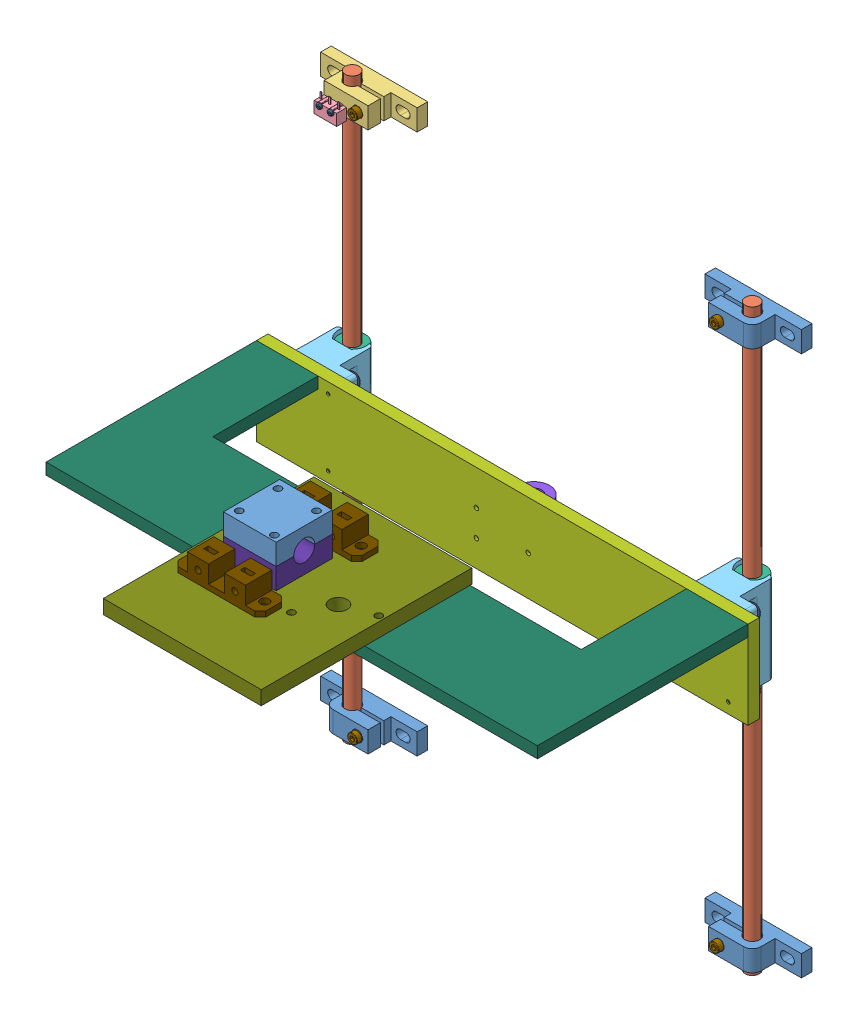
SolidWorks assembly moving assembly, configuration Default. Lengths in mm.
Overall size (280 330 218.5).
61 component instances, 19 part files, 106 mates.
Components (placement in the parent):
- bar_and_mounts-1: bar_and_mounts [Default] at (-49.2169 -149.0461 22.6055) size (55 330 19)
  - bar_mount-1: bar_mount [Default] at (-61.595 -12.5462 12.9389) size (55 12 19)
  - bar_mount-2: bar_mount [Default] at (-61.595 295.4538 12.9389) size (55 12 19)
  - bar-1: bar [Default] at (-29.595 -17.5462 23.9389) size (8 330 8)
- bar_and_mounts_switch-1: bar_and_mounts_switch [Default] at (-356.8295 169.2155 27.6951) x (-1 0 0) z (0 0 1) size (55 330 24.7)
  - bar_mount_switch-1: bar_mount_switch [Default] at (-82.0176 10.8078 7.8492) size (55 12 19)
  - bar-1: bar [Default] at (-50.0176 5.8078 18.8492) size (8 330 8)
  - bar_mount-1: bar_mount [Default] at (-82.0176 318.8078 7.8492) size (55 12 19)
  - switch-1: switch [Default] at (-54.8176 17.8078 26.8492) x (1 0 0) z (0 -1 0) size (12.8 5.7 10.85)
- pusher_bearing_mount-1: pusher_bearing_mount [Default] at (-93.535 -18.6939 68.5444) size (40 50 27.5)
- pusher_bearing_mount-2: pusher_bearing_mount [Default] at (-321.535 -18.6939 68.5444) size (40 50 27.5)
- lm8uul-1: lm8uul [Default] at (-78.8119 -15.6939 46.5444) size (15 45 15)
- lm8uul-2: lm8uul [Default] at (-306.8119 -15.6939 46.5444) size (15 45 15)
- pusher_plank-1: pusher_plank [Default] at (-332.8119 -18.6939 68.5444) x (1 0 0) z (0 -1 0) size (280 6.5 50)
- pusher_mount-1: pusher_mount [Default] at (-192.8119 -8.6939 68.5444) size (40 25 20.5)
- socket head cap screw_din-2: socket head cap screw_din [DIN 912 M3 x 16 --- 16N] at (-89.8119 152.4077 57.5444) x (0 0 -1) z (1 0 0) size (19 5.5 5.5)
- socket head cap screw_din-3: socket head cap screw_din [DIN 912 M3 x 16 --- 16N] at (-295.8119 152.4077 57.5444) x (0 0 -1) z (1 0 0) size (19 5.5 5.5)
- socket head cap screw_din-4: socket head cap screw_din [DIN 912 M3 x 16 --- 16N] at (-295.8119 -155.5923 57.5444) x (0 0 -1) z (1 0 0) size (19 5.5 5.5)
- socket head cap screw_din-5: socket head cap screw_din [DIN 912 M3 x 16 --- 16N] at (-89.8119 -155.5923 57.5444) x (0 0 -1) z (1 0 0) size (19 5.5 5.5)
- slotted pan head screw_din-1: slotted pan head screw_din [ISO 1580 - M1.6 x 8 --- 8N] at (-311.6619 150.4077 61.2444) x (0 0 -1) z (1 0 0) size (9.03 3.2 3.2)
- slotted pan head screw_din-4: slotted pan head screw_din [ISO 1580 - M1.6 x 8 --- 8N] at (-305.1619 150.4077 61.2444) x (0 0 -1) z (1 0 0) size (9.03 3.2 3.2)
- slotted pan head screw_din-8: slotted pan head screw_din [ISO 1580 - M4 x 10 --- 10N] at (-207.5619 11.3061 61.1444) x (0 0 1) z (-1 0 0) size (12.47 8 8)
- slotted pan head screw_din-9: slotted pan head screw_din [ISO 1580 - M4 x 10 --- 10N] at (-178.0619 3.8061 61.1444) x (0 0 1) z (-1 0 0) size (12.47 8 8)
- slotted pan head screw_din-10: slotted pan head screw_din [ISO 1580 - M4 x 10 --- 10N] at (-207.5619 -3.6939 61.1444) x (0 0 1) z (-1 0 0) size (12.47 8 8)
- prevailing torque nut style 1 insert_din-1: prevailing torque nut style 1 insert_din [DIN EN ISO 7040 - M3 - N] at (-89.8119 152.4077 41.3944) x (0.923728 0.383049 0) z (0 0 -1) size (5.5 6.35 4.5)
- prevailing torque nut style 1 insert_din-2: prevailing torque nut style 1 insert_din [DIN EN ISO 7040 - M3 - N] at (-89.8119 -155.5923 41.3944) x (0.923728 0.383049 0) z (0 0 -1) size (5.5 6.35 4.5)
- prevailing torque nut style 1 insert_din-3: prevailing torque nut style 1 insert_din [DIN EN ISO 7040 - M3 - N] at (-295.8119 -155.5923 41.3944) x (0.923728 0.383049 0) z (0 0 -1) size (5.5 6.35 4.5)
- prevailing torque nut style 1 insert_din-4: prevailing torque nut style 1 insert_din [DIN EN ISO 7040 - M3 - N] at (-295.8119 152.4077 41.3944) x (-0.923728 -0.383049 0) z (0 0 -1) size (5.5 6.35 4.5)
- toothed lock washer 1_din-1: toothed lock washer 1_din [DIN 6797-A3.2] at (-295.8119 152.4077 54.1444) x (0 0 -1) z (1 0 0) size (0.4 5.93 6)
- toothed lock washer 1_din-2: toothed lock washer 1_din [DIN 6797-A3.2] at (-89.8119 152.4077 54.1444) x (0 0 -1) z (1 0 0) size (0.4 5.93 6)
- toothed lock washer 1_din-3: toothed lock washer 1_din [DIN 6797-A3.2] at (-89.8119 -155.5923 54.1444) x (0 0 -1) z (1 0 0) size (0.4 5.93 6)
- toothed lock washer 1_din-4: toothed lock washer 1_din [DIN 6797-A3.2] at (-295.8119 -155.5923 54.9444) x (0 0 1) z (-1 0 0) size (0.4 5.93 6)
- plain washer 6902 type abc_din-2: plain washer 6902 type abc_din [DIN 6902-A3.6] at (-207.5619 -3.6939 63.5444) x (0 0 1) z (-1 0 0) size (0.8 9 9)
- plain washer 6902 type abc_din-3: plain washer 6902 type abc_din [DIN 6902-A3.6] at (-207.5619 11.3061 63.5444) x (0 0 1) z (-1 0 0) size (0.8 9 9)
- plain washer 6902 type abc_din-4: plain washer 6902 type abc_din [DIN 6902-A3.6] at (-178.0619 3.8061 63.5444) x (0 0 1) z (-1 0 0) size (0.8 9 9)
- hex nut gradec_din-1: hex nut gradec_din [Hexagon Nut ISO 4034 - M8 - N] at (-192.8119 7.7061 57.0444) x (1 0 0) z (0 1 0) size (13 15.01 7.9)
- plain washer 6902 type abc_din-5: plain washer 6902 type abc_din [DIN 6902-A3.6] at (-321.5619 6.3061 62.7444) x (0 0 1) z (-1 0 0) size (0.8 9 9)
- plain washer 6902 type abc_din-6: plain washer 6902 type abc_din [DIN 6902-A3.6] at (-292.0619 -12.6939 63.5444) x (0 0 -1) z (1 0 0) size (0.8 9 9)
- plain washer 6902 type abc_din-7: plain washer 6902 type abc_din [DIN 6902-A3.6] at (-292.0619 25.3061 63.5444) x (0 0 -1) z (1 0 0) size (0.8 9 9)
- plain washer 6902 type abc_din-8: plain washer 6902 type abc_din [DIN 6902-A3.6] at (-64.0134 -12.6939 63.5444) x (0 0 -1) z (1 0 0) size (0.8 9 9)
- plain washer 6902 type abc_din-9: plain washer 6902 type abc_din [DIN 6902-A3.6] at (-93.5619 6.3061 63.5444) x (0 0 -1) z (1 0 0) size (0.8 9 9)
- plain washer 6902 type abc_din-10: plain washer 6902 type abc_din [DIN 6902-A3.6] at (-64.0134 25.3061 63.5444) x (0 0 -1) z (1 0 0) size (0.8 9 9)
- toothed lock washer 1_din-5: toothed lock washer 1_din [DIN 6797-A4.3] at (-93.5619 6.3061 62.2444) x (0 0 -1) z (1 0 0) size (0.5 7.91 7.91)
- toothed lock washer 1_din-6: toothed lock washer 1_din [DIN 6797-A4.3] at (-64.0134 -12.6939 62.2444) x (0 0 -1) z (1 0 0) size (0.5 7.91 7.91)
- toothed lock washer 1_din-7: toothed lock washer 1_din [DIN 6797-A4.3] at (-64.0134 25.3061 62.2444) x (0 0 -1) z (1 0 0) size (0.5 7.91 7.91)
- toothed lock washer 1_din-8: toothed lock washer 1_din [DIN 6797-A4.3] at (-292.0619 -12.6939 62.2444) x (0 0 -1) z (1 0 0) size (0.5 7.91 7.91)
- toothed lock washer 1_din-9: toothed lock washer 1_din [DIN 6797-A4.3] at (-292.0619 25.3061 62.2444) x (0 0 -1) z (1 0 0) size (0.5 7.91 7.91)
- toothed lock washer 1_din-11: toothed lock washer 1_din [DIN 6797-A4.3] at (-321.5619 6.3061 62.2444) x (0 0 -1) z (1 0 0) size (0.5 7.91 7.91)
- slotted pan head screw_din-11: slotted pan head screw_din [ISO 1580 - M4 x 12 --- 12N] at (-93.5619 6.3061 59.8444) x (0 0 1) z (-1 0 0) size (14.47 8 8)
- slotted pan head screw_din-12: slotted pan head screw_din [ISO 1580 - M4 x 12 --- 12N] at (-64.0134 25.3061 59.8444) x (0 0 1) z (-1 0 0) size (14.47 8 8)
- slotted pan head screw_din-13: slotted pan head screw_din [ISO 1580 - M4 x 12 --- 12N] at (-64.0134 -12.6939 59.8444) x (0 0 1) z (-1 0 0) size (14.47 8 8)
- slotted pan head screw_din-14: slotted pan head screw_din [ISO 1580 - M4 x 12 --- 12N] at (-321.5619 6.3061 59.8444) x (0 0 1) z (-1 0 0) size (14.47 8 8)
- slotted pan head screw_din-15: slotted pan head screw_din [ISO 1580 - M4 x 12 --- 12N] at (-292.0619 25.3061 59.8444) x (0 0 1) z (-1 0 0) size (14.47 8 8)
- slotted pan head screw_din-16: slotted pan head screw_din [ISO 1580 - M4 x 12 --- 12N] at (-292.0619 -12.6939 59.8444) x (0 0 1) z (-1 0 0) size (14.47 8 8)
- carret-1: carret [Default] at (-332.8119 31.3061 75.0444) x (1 0 0) z (0 0 -1) size (280 6.5 120)
- head_assembly-1: head_assembly [Default] at (-193.7359 2.3231 248.2305) x (1 0 0) z (0 1 0) size (90 120 32)
  - laserhead_base-1: laserhead_base [Default] at (-47.4396 -5.8139 28.9831) size (90 120 8)
  - mount-1: mount [Default] at (-1.9396 79.1861 36.9831) x (0 -1 0) z (-1 0 0) size (32 12 30)
  - calibration-1: calibration [Default] at (-41.9396 28.1861 36.9831) size (50 15 13)
  - calibration-2: calibration [Default] at (-41.9396 83.1861 36.9831) size (50 15 13)
  - mount_top-1: mount_top [Default] at (-31.9396 79.1861 60.9831) x (1 0 0) z (0 1 0) size (30 12 32)
Mates (geometry in assembly coordinates):
- Coincident2: coincident aligned: plane of bar_and_mounts-1/bar_mount-1 through (-110.8119 -161.5923 41.5444) normal (0 -1 0); plane of bar_and_mounts_switch-1/bar_mount-1 through (-274.8119 -161.5923 41.5444) normal (0 -1 0)
- Coincident3: coincident aligned: plane of bar_and_mounts-1/bar_mount-1 through (-110.8119 -161.5923 35.5444) normal (0 0 -1); plane of bar_and_mounts_switch-1/bar_mount-1 through (-274.8119 -149.5923 35.5444) normal (0 0 -1)
- Concentric1: concentric: cylinder of ? through (-78.8119 69.654 46.5444) axis (0 -1 0) radius 7.5; cylinder of pusher_bearing_mount-1 through (-78.8119 72.154 46.5444) axis (0 -1 0) radius 7.5468
- Coincident4: coincident anti-aligned: plane of ? through (-78.8119 24.654 46.5444) normal (0 -1 0); plane of pusher_bearing_mount-1 through (-71.535 24.654 62.5444) normal (0 1 0)
- Concentric2: concentric: cylinder of ? through (-218.3938 50.2542 46.5444) axis (0 1 0) radius 7.5; cylinder of pusher_bearing_mount-2 through (-218.3938 97.7542 46.5444) axis (0 -1 0) radius 7.5468
- Coincident5: coincident anti-aligned: plane of ? through (-218.3938 50.2542 46.5444) normal (0 -1 0); plane of pusher_bearing_mount-2 through (-211.1168 50.2542 62.5444) normal (0 1 0)
- Concentric3: concentric aligned: cylinder of bar_and_mounts-1/bar-1 through (-78.8119 163.4077 46.5444) axis (0 -1 0) radius 4; cylinder of lm8uul-1 through (-78.8119 29.3061 46.5444) axis (0 -1 0) radius 4
- Concentric4: concentric aligned: cylinder of pusher_bearing_mount-1 through (-78.8119 31.3061 46.5444) axis (0 -1 0) radius 7.9; cylinder of lm8uul-1 through (-78.8119 29.3061 46.5444) axis (0 -1 0) radius 7.5
- Coincident6: coincident anti-aligned: plane of pusher_bearing_mount-1 through (-71.1693 29.3061 62.5444) normal (0 -1 0); plane of lm8uul-1 through (-78.8119 29.3061 46.5444) normal (0 1 0)
- Concentric5: concentric anti-aligned: cylinder of bar_and_mounts_switch-1/bar-1 through (-306.8119 -166.5923 46.5444) axis (0 1 0) radius 4; cylinder of lm8uul-2 through (-306.8119 29.3061 46.5444) axis (0 -1 0) radius 4
- Coincident7: coincident anti-aligned: plane of pusher_bearing_mount-2 through (-299.1693 29.3061 62.5444) normal (0 -1 0); plane of lm8uul-2 through (-306.8119 29.3061 46.5444) normal (0 1 0)
- Concentric6: concentric aligned: cylinder of pusher_bearing_mount-2 through (-306.8119 31.3061 46.5444) axis (0 -1 0) radius 7.9; cylinder of lm8uul-2 through (-306.8119 29.3061 46.5444) axis (0 -1 0) radius 7.5
- Parallel1: parallel anti-aligned: plane of bar_and_mounts-1/bar_mount-1 through (-110.8119 -161.5923 35.5444) normal (0 0 -1); plane of pusher_bearing_mount-1 through (-98.8119 31.3061 68.5444) normal (0 0 1)
- Parallel2: parallel anti-aligned: plane of bar_and_mounts_switch-1/bar_mount-1 through (-274.8119 -149.5923 35.5444) normal (0 0 -1); plane of pusher_bearing_mount-2 through (-326.8119 31.3061 68.5444) normal (0 0 1)
- Coincident10: coincident aligned: plane of pusher_bearing_mount-1 through (-78.8119 -18.6939 46.5444) normal (0 -1 0); plane of pusher_bearing_mount-2 through (-306.8119 -18.6939 46.5444) normal (0 -1 0)
- Coincident11: coincident anti-aligned: plane of pusher_bearing_mount-2 through (-326.8119 31.3061 68.5444) normal (0 0 1); plane of pusher_plank-1 through (-332.8119 -18.6939 68.5444) normal (0 0 -1)
- Coincident12: coincident aligned: plane of pusher_bearing_mount-2 through (-306.8119 -18.6939 46.5444) normal (0 -1 0); plane of pusher_plank-1 through (-332.8119 -18.6939 75.0444) normal (0 -1 0)
- Distance1: distance = 220 mm: cylinder of bar_and_mounts_switch-1/bar-1 through (-306.8119 -166.5923 46.5444) axis (0 1 0) radius 4; cylinder of bar_and_mounts-1/bar-1 through (-78.8119 163.4077 46.5444) axis (0 -1 0) radius 4
- Distance2: distance = 6 mm aligned: plane of pusher_plank-1 through (-332.8119 -18.6939 75.0444) normal (-1 0 0); plane of pusher_bearing_mount-2 through (-326.8119 31.3061 68.5444) normal (-1 0 0)
- Coincident13: coincident anti-aligned: plane of pusher_plank-1 through (-332.8119 -18.6939 68.5444) normal (0 0 -1); plane of pusher_mount-1 through (-172.8119 16.3061 68.5444) normal (0 0 1)
- Distance3: distance = 10 mm aligned: plane of pusher_mount-1 through (-192.8119 -8.6939 57.0444) normal (0 -1 0); plane of pusher_plank-1 through (-332.8119 -18.6939 75.0444) normal (0 -1 0)
- Distance4: distance = 74 mm anti-aligned: plane of pusher_mount-1 through (-212.8119 16.3061 68.5444) normal (-1 0 0); plane of pusher_bearing_mount-2 through (-286.8119 31.3061 68.5444) normal (1 0 0)
- Concentric7: concentric aligned: cylinder of bar_and_mounts-1/bar_mount-2 through (-89.8119 152.4077 43.5444) axis (0 0 1) radius 1.6; cylinder of socket head cap screw_din-2 through (-89.8119 152.4077 89.2944) axis (0 0 1) radius 2.75
- Coincident14: coincident anti-aligned: plane of bar_and_mounts-1/bar_mount-2 through (-110.8119 146.4077 54.5444) normal (0 0 1); plane of socket head cap screw_din-2 through (-89.8119 155.1577 54.5444) normal (0 0 -1)
- Concentric8: concentric aligned: cylinder of bar_and_mounts_switch-1/bar_mount_switch-1 through (-295.8119 152.4077 43.5444) axis (0 0 1) radius 1.6; cylinder of socket head cap screw_din-3 through (-295.8119 152.4077 89.2944) axis (0 0 1) radius 2.75
- Coincident15: coincident anti-aligned: plane of bar_and_mounts_switch-1/bar_mount_switch-1 through (-274.8119 158.4077 54.5444) normal (0 0 1); plane of socket head cap screw_din-3 through (-295.8119 155.1577 54.5444) normal (0 0 -1)
- Concentric9: concentric aligned: cylinder of bar_and_mounts_switch-1/bar_mount-1 through (-295.8119 -155.5923 43.5444) axis (0 0 1) radius 1.6; cylinder of socket head cap screw_din-4 through (-295.8119 -155.5923 89.2944) axis (0 0 1) radius 2.75
- Coincident16: coincident anti-aligned: plane of bar_and_mounts_switch-1/bar_mount-1 through (-274.8119 -149.5923 54.5444) normal (0 0 1); plane of socket head cap screw_din-4 through (-295.8119 -152.8423 54.5444) normal (0 0 -1)
- Concentric10: concentric aligned: cylinder of bar_and_mounts-1/bar_mount-1 through (-89.8119 -155.5923 43.5444) axis (0 0 1) radius 1.6; cylinder of socket head cap screw_din-5 through (-89.8119 -155.5923 89.2944) axis (0 0 1) radius 2.75
- Coincident17: coincident anti-aligned: plane of bar_and_mounts-1/bar_mount-1 through (-110.8119 -161.5923 54.5444) normal (0 0 1); plane of socket head cap screw_din-5 through (-89.8119 -152.8423 54.5444) normal (0 0 -1)
- Concentric12: concentric anti-aligned: cylinder of bar_and_mounts_switch-1/switch-1 through (-311.6619 150.4077 60.2444) axis (0 0 -1) radius 1; cylinder of slotted pan head screw_din-1 through (-311.6619 150.4077 86.6444) axis (0 0 1) radius 0.8
- Coincident18: coincident anti-aligned: plane of bar_and_mounts_switch-1/switch-1 through (-312.3619 151.6077 60.2444) normal (0 0 1); plane of slotted pan head screw_din-1 through (-311.6619 151.2077 60.2444) normal (0 0 -1)
- Concentric13: concentric anti-aligned: cylinder of bar_and_mounts_switch-1/switch-1 through (-305.1619 150.4077 60.2444) axis (0 0 -1) radius 1; cylinder of slotted pan head screw_din-4 through (-305.1619 150.4077 86.6444) axis (0 0 1) radius 0.8
- Coincident20: coincident anti-aligned: plane of bar_and_mounts_switch-1/switch-1 through (-312.3619 151.6077 60.2444) normal (0 0 1); plane of slotted pan head screw_din-4 through (-305.1619 151.2077 60.2444) normal (0 0 -1)
- Coincident23: coincident anti-aligned: plane of pusher_mount-1 through (-201.8119 16.3061 63.5444) normal (0 0 -1); plane of slotted pan head screw_din-8 through (-207.5619 13.3061 63.5444) normal (0 0 1)
- Concentric17: concentric aligned: cylinder of pusher_plank-1 through (-178.0619 3.8061 75.0444) axis (0 0 -1) radius 1.25; cylinder of slotted pan head screw_din-9 through (-178.0619 3.8061 35.7444) axis (0 0 -1) radius 2
- Coincident24: coincident anti-aligned: plane of pusher_mount-1 through (-201.8119 16.3061 63.5444) normal (0 0 -1); plane of slotted pan head screw_din-10 through (-207.5619 -1.6939 63.5444) normal (0 0 1)
- Concentric21: concentric aligned: cylinder of pusher_plank-1 through (-207.5619 -3.6939 75.0444) axis (0 0 -1) radius 1.25; cylinder of slotted pan head screw_din-10 through (-207.5619 -3.6939 35.7444) axis (0 0 -1) radius 2
- Coincident25: coincident anti-aligned: plane of pusher_mount-1 through (-183.8119 16.3061 63.5444) normal (0 0 -1); plane of slotted pan head screw_din-9 through (-178.0619 5.8061 63.5444) normal (0 0 1)
- Concentric22: concentric aligned: cylinder of pusher_plank-1 through (-207.5619 11.3061 75.0444) axis (0 0 -1) radius 1.25; cylinder of slotted pan head screw_din-8 through (-207.5619 11.3061 35.7444) axis (0 0 -1) radius 2
- Concentric23: concentric anti-aligned: cylinder of socket head cap screw_din-2 through (-89.8119 152.4077 89.2944) axis (0 0 1) radius 1.5; cylinder of prevailing torque nut style 1 insert_din-1 through (-89.8119 152.4077 66.4319) axis (0 0 -1) radius 1.5
- Concentric24: concentric anti-aligned: cylinder of bar_and_mounts-1/bar_mount-1 through (-89.8119 -155.5923 43.5444) axis (0 0 1) radius 1.6; cylinder of prevailing torque nut style 1 insert_din-2 through (-89.8119 -155.5923 66.4319) axis (0 0 -1) radius 1.5
- Coincident26: coincident anti-aligned: plane of bar_and_mounts-1/bar_mount-1 through (-110.8119 -161.5923 43.5444) normal (0 0 -1); plane of prevailing torque nut style 1 insert_din-2 through (-94.8924 -157.6991 43.5444) normal (0 0 1)
- Concentric25: concentric anti-aligned: cylinder of bar_and_mounts_switch-1/bar_mount-1 through (-295.8119 -155.5923 43.5444) axis (0 0 1) radius 1.6; cylinder of prevailing torque nut style 1 insert_din-3 through (-295.8119 -155.5923 66.4319) axis (0 0 -1) radius 1.5
- Coincident27: coincident anti-aligned: plane of bar_and_mounts_switch-1/bar_mount-1 through (-274.8119 -149.5923 43.5444) normal (0 0 -1); plane of prevailing torque nut style 1 insert_din-3 through (-300.8924 -157.6991 43.5444) normal (0 0 1)
- Coincident28: coincident anti-aligned: plane of bar_and_mounts_switch-1/bar_mount_switch-1 through (-274.8119 158.4077 43.5444) normal (0 0 -1); plane of prevailing torque nut style 1 insert_din-4 through (-290.7314 154.5145 43.5444) normal (0 0 1)
- Concentric26: concentric anti-aligned: cylinder of socket head cap screw_din-3 through (-295.8119 152.4077 89.2944) axis (0 0 1) radius 1.5; cylinder of prevailing torque nut style 1 insert_din-4 through (-295.8119 152.4077 43.5444) axis (0 0 -1) radius 1.25
- Coincident29: coincident anti-aligned: plane of bar_and_mounts-1/bar_mount-2 through (-110.8119 146.4077 43.5444) normal (0 0 -1); plane of prevailing torque nut style 1 insert_din-1 through (-94.8924 150.3009 43.5444) normal (0 0 1)
- Concentric27: concentric anti-aligned: cylinder of bar_and_mounts_switch-1/bar_mount_switch-1 through (-295.8119 152.4077 43.5444) axis (0 0 1) radius 1.6; cylinder of toothed lock washer 1_din-1 through (-295.8119 152.4077 54.5444) axis (0 0 -1) radius 3
- Coincident30: coincident anti-aligned: plane of socket head cap screw_din-3 through (-295.8119 155.1577 54.5444) normal (0 0 -1); plane of toothed lock washer 1_din-1 through (-295.8119 152.4077 54.5444) normal (0 0 1)
- Concentric28: concentric anti-aligned: cylinder of bar_and_mounts-1/bar_mount-2 through (-89.8119 152.4077 43.5444) axis (0 0 1) radius 1.6; cylinder of toothed lock washer 1_din-2 through (-89.8119 152.4077 54.5444) axis (0 0 -1) radius 3
- Coincident31: coincident anti-aligned: plane of socket head cap screw_din-2 through (-89.8119 155.1577 54.5444) normal (0 0 -1); plane of toothed lock washer 1_din-2 through (-89.8119 152.4077 54.5444) normal (0 0 1)
- Concentric29: concentric anti-aligned: cylinder of bar_and_mounts-1/bar_mount-1 through (-89.8119 -155.5923 43.5444) axis (0 0 1) radius 1.6; cylinder of toothed lock washer 1_din-3 through (-89.8119 -155.5923 54.5444) axis (0 0 -1) radius 3
- Coincident32: coincident anti-aligned: plane of socket head cap screw_din-5 through (-89.8119 -152.8423 54.5444) normal (0 0 -1); plane of toothed lock washer 1_din-3 through (-89.8119 -155.5923 54.5444) normal (0 0 1)
- Concentric30: concentric aligned: cylinder of bar_and_mounts_switch-1/bar_mount-1 through (-295.8119 -155.5923 43.5444) axis (0 0 1) radius 1.6; cylinder of toothed lock washer 1_din-4 through (-295.8119 -155.5923 54.5444) axis (0 0 1) radius 3
- Coincident33: coincident anti-aligned: plane of bar_and_mounts_switch-1/bar_mount-1 through (-274.8119 -149.5923 54.5444) normal (0 0 1); plane of toothed lock washer 1_din-4 through (-295.8119 -155.5923 54.5444) normal (0 0 -1)
- Concentric32: concentric aligned: cone of slotted pan head screw_din-10 through (-207.5619 -3.6939 61.1444) axis (0 0 -1); cylinder of plain washer 6902 type abc_din-2 through (-207.5619 -3.6939 64.3444) axis (0 0 -1) radius 1.8
- Coincident35: coincident anti-aligned: plane of slotted pan head screw_din-10 through (-207.5619 -1.6939 63.5444) normal (0 0 1); plane of plain washer 6902 type abc_din-2 through (-207.5619 -3.6939 63.5444) normal (0 0 -1)
- Concentric33: concentric aligned: cone of slotted pan head screw_din-8 through (-207.5619 11.3061 61.1444) axis (0 0 -1); cylinder of plain washer 6902 type abc_din-3 through (-207.5619 11.3061 64.3444) axis (0 0 -1) radius 1.8
- Coincident36: coincident anti-aligned: plane of slotted pan head screw_din-8 through (-207.5619 13.3061 63.5444) normal (0 0 1); plane of plain washer 6902 type abc_din-3 through (-207.5619 11.3061 63.5444) normal (0 0 -1)
- Concentric34: concentric aligned: cone of slotted pan head screw_din-9 through (-178.0619 3.8061 61.1444) axis (0 0 -1); cylinder of plain washer 6902 type abc_din-4 through (-178.0619 3.8061 64.3444) axis (0 0 -1) radius 1.8
- Coincident37: coincident anti-aligned: plane of slotted pan head screw_din-9 through (-178.0619 5.8061 63.5444) normal (0 0 1); plane of plain washer 6902 type abc_din-4 through (-178.0619 3.8061 63.5444) normal (0 0 -1)
- Concentric35: concentric anti-aligned: cylinder of pusher_mount-1 through (-192.8119 16.3061 57.0444) axis (0 -1 0) radius 4.5; cylinder of hex nut gradec_din-1 through (-192.8119 -17.3314 57.0444) axis (0 1 0) radius 4
- Coincident38: coincident anti-aligned: plane of pusher_mount-1 through (-192.8119 -0.1939 68.5444) normal (0 1 0); plane of hex nut gradec_din-1 through (-192.8119 -0.1939 49.5388) normal (0 -1 0)
- Coincident39: coincident anti-aligned: plane of pusher_bearing_mount-2 through (-296.8119 31.3061 63.5444) normal (0 0 -1); plane of plain washer 6902 type abc_din-6 through (-292.0619 -12.6939 63.5444) normal (0 0 1)
- Coincident40: coincident anti-aligned: plane of pusher_bearing_mount-2 through (-296.8119 31.3061 63.5444) normal (0 0 -1); plane of plain washer 6902 type abc_din-7 through (-292.0619 25.3061 63.5444) normal (0 0 1)
- Coincident41: coincident anti-aligned: plane of pusher_bearing_mount-1 through (-68.8119 31.3061 63.5444) normal (0 0 -1); plane of plain washer 6902 type abc_din-8 through (-64.0134 -12.6939 63.5444) normal (0 0 1)
- Coincident42: coincident anti-aligned: plane of pusher_bearing_mount-1 through (-88.8119 31.3061 63.5444) normal (0 0 -1); plane of plain washer 6902 type abc_din-9 through (-93.5619 6.3061 63.5444) normal (0 0 1)
- Coincident43: coincident anti-aligned: plane of pusher_bearing_mount-1 through (-68.8119 31.3061 63.5444) normal (0 0 -1); plane of plain washer 6902 type abc_din-10 through (-64.0134 25.3061 63.5444) normal (0 0 1)
- Concentric41: concentric anti-aligned: cylinder of plain washer 6902 type abc_din-9 through (-93.5619 6.3061 62.7444) axis (0 0 1) radius 1.8; cylinder of toothed lock washer 1_din-5 through (-93.5619 6.3061 62.7444) axis (0 0 -1) radius 4
- Coincident44: coincident anti-aligned: plane of plain washer 6902 type abc_din-9 through (-93.5619 6.3061 62.7444) normal (0 0 -1); plane of toothed lock washer 1_din-5 through (-93.5619 6.3061 62.7444) normal (0 0 1)
- Concentric42: concentric anti-aligned: cylinder of plain washer 6902 type abc_din-8 through (-64.0134 -12.6939 62.7444) axis (0 0 1) radius 1.8; cylinder of toothed lock washer 1_din-6 through (-64.0134 -12.6939 62.7444) axis (0 0 -1) radius 4
- Coincident45: coincident anti-aligned: plane of plain washer 6902 type abc_din-8 through (-64.0134 -12.6939 62.7444) normal (0 0 -1); plane of toothed lock washer 1_din-6 through (-64.0134 -12.6939 62.7444) normal (0 0 1)
- Concentric43: concentric anti-aligned: cylinder of plain washer 6902 type abc_din-10 through (-64.0134 25.3061 62.7444) axis (0 0 1) radius 1.8; cylinder of toothed lock washer 1_din-7 through (-64.0134 25.3061 62.7444) axis (0 0 -1) radius 4
- Coincident46: coincident anti-aligned: plane of plain washer 6902 type abc_din-10 through (-64.0134 25.3061 62.7444) normal (0 0 -1); plane of toothed lock washer 1_din-7 through (-64.0134 25.3061 62.7444) normal (0 0 1)
- Concentric44: concentric anti-aligned: cylinder of plain washer 6902 type abc_din-6 through (-292.0619 -12.6939 62.7444) axis (0 0 1) radius 1.8; cylinder of toothed lock washer 1_din-8 through (-292.0619 -12.6939 62.7444) axis (0 0 -1) radius 4
- Coincident47: coincident anti-aligned: plane of plain washer 6902 type abc_din-6 through (-292.0619 -12.6939 62.7444) normal (0 0 -1); plane of toothed lock washer 1_din-8 through (-292.0619 -12.6939 62.7444) normal (0 0 1)
- Concentric45: concentric anti-aligned: cylinder of plain washer 6902 type abc_din-7 through (-292.0619 25.3061 62.7444) axis (0 0 1) radius 4.5; cylinder of toothed lock washer 1_din-9 through (-292.0619 25.3061 62.7444) axis (0 0 -1) radius 4
- Coincident48: coincident anti-aligned: plane of plain washer 6902 type abc_din-7 through (-292.0619 25.3061 62.7444) normal (0 0 -1); plane of toothed lock washer 1_din-9 through (-292.0619 25.3061 62.7444) normal (0 0 1)
- Coincident53: coincident anti-aligned: plane of pusher_bearing_mount-2 through (-316.8119 31.3061 63.5444) normal (0 0 -1); plane of plain washer 6902 type abc_din-5 through (-321.5619 6.3061 63.5444) normal (0 0 1)
- Concentric49: concentric aligned: cylinder of pusher_plank-1 through (-321.5619 6.3061 75.0444) axis (0 0 -1) radius 1; cylinder of plain washer 6902 type abc_din-5 through (-321.5619 6.3061 63.5444) axis (0 0 -1) radius 1.8
- Concentric50: concentric aligned: cylinder of plain washer 6902 type abc_din-5 through (-321.5619 6.3061 63.5444) axis (0 0 -1) radius 1.8; cylinder of toothed lock washer 1_din-11 through (-321.5619 6.3061 62.7444) axis (0 0 -1) radius 4
- Coincident54: coincident anti-aligned: plane of plain washer 6902 type abc_din-5 through (-321.5619 6.3061 62.7444) normal (0 0 -1); plane of toothed lock washer 1_din-11 through (-321.5619 6.3061 62.7444) normal (0 0 1)
- Concentric52: concentric anti-aligned: cylinder of pusher_plank-1 through (-292.0619 25.3061 75.0444) axis (0 0 -1) radius 1; cylinder of plain washer 6902 type abc_din-7 through (-292.0619 25.3061 62.7444) axis (0 0 1) radius 1.8
- Concentric53: concentric anti-aligned: cylinder of pusher_plank-1 through (-292.0619 -12.6939 75.0444) axis (0 0 -1) radius 1; cylinder of plain washer 6902 type abc_din-6 through (-292.0619 -12.6939 62.7444) axis (0 0 1) radius 1.8
- Concentric54: concentric anti-aligned: cylinder of pusher_plank-1 through (-64.0134 -12.6939 75.0444) axis (0 0 -1) radius 1; cylinder of plain washer 6902 type abc_din-8 through (-64.0134 -12.6939 62.7444) axis (0 0 1) radius 1.8
- Concentric55: concentric anti-aligned: cylinder of pusher_plank-1 through (-64.0134 25.3061 75.0444) axis (0 0 -1) radius 1; cylinder of plain washer 6902 type abc_din-10 through (-64.0134 25.3061 62.7444) axis (0 0 1) radius 1.8
- Concentric56: concentric anti-aligned: cylinder of pusher_plank-1 through (-93.5619 6.3061 75.0444) axis (0 0 -1) radius 1; cylinder of plain washer 6902 type abc_din-9 through (-93.5619 6.3061 62.7444) axis (0 0 1) radius 1.8
- Concentric57: concentric aligned: cylinder of toothed lock washer 1_din-5 through (-93.5619 6.3061 62.7444) axis (0 0 -1) radius 2.15; cylinder of slotted pan head screw_din-11 through (-93.5619 6.3061 34.4444) axis (0 0 -1) radius 2
- Coincident55: coincident anti-aligned: plane of toothed lock washer 1_din-5 through (-93.5619 6.3061 62.2444) normal (0 0 -1); plane of slotted pan head screw_din-11 through (-93.5619 8.3061 62.2444) normal (0 0 1)
- Concentric58: concentric aligned: cylinder of toothed lock washer 1_din-7 through (-64.0134 25.3061 62.7444) axis (0 0 -1) radius 2.15; cylinder of slotted pan head screw_din-12 through (-64.0134 25.3061 34.4444) axis (0 0 -1) radius 2
- Coincident56: coincident anti-aligned: plane of toothed lock washer 1_din-7 through (-64.0134 25.3061 62.2444) normal (0 0 -1); plane of slotted pan head screw_din-12 through (-64.0134 27.3061 62.2444) normal (0 0 1)
- Concentric59: concentric aligned: cylinder of toothed lock washer 1_din-6 through (-64.0134 -12.6939 62.7444) axis (0 0 -1) radius 2.15; cylinder of slotted pan head screw_din-13 through (-64.0134 -12.6939 34.4444) axis (0 0 -1) radius 2
- Coincident57: coincident anti-aligned: plane of toothed lock washer 1_din-6 through (-64.0134 -12.6939 62.2444) normal (0 0 -1); plane of slotted pan head screw_din-13 through (-64.0134 -10.6939 62.2444) normal (0 0 1)
- Concentric60: concentric aligned: cylinder of toothed lock washer 1_din-11 through (-321.5619 6.3061 62.7444) axis (0 0 -1) radius 2.15; cylinder of slotted pan head screw_din-14 through (-321.5619 6.3061 34.4444) axis (0 0 -1) radius 2
- Coincident58: coincident anti-aligned: plane of toothed lock washer 1_din-11 through (-321.5619 6.3061 62.2444) normal (0 0 -1); plane of slotted pan head screw_din-14 through (-321.5619 8.3061 62.2444) normal (0 0 1)
- Concentric61: concentric aligned: cylinder of toothed lock washer 1_din-9 through (-292.0619 25.3061 62.7444) axis (0 0 -1) radius 2.15; cylinder of slotted pan head screw_din-15 through (-292.0619 25.3061 34.4444) axis (0 0 -1) radius 2
- Coincident59: coincident anti-aligned: plane of toothed lock washer 1_din-9 through (-292.0619 25.3061 62.2444) normal (0 0 -1); plane of slotted pan head screw_din-15 through (-292.0619 27.3061 62.2444) normal (0 0 1)
- Concentric62: concentric aligned: cylinder of toothed lock washer 1_din-8 through (-292.0619 -12.6939 62.7444) axis (0 0 -1) radius 2.15; cylinder of slotted pan head screw_din-16 through (-292.0619 -12.6939 34.4444) axis (0 0 -1) radius 2
- Coincident60: coincident anti-aligned: plane of toothed lock washer 1_din-8 through (-292.0619 -12.6939 62.2444) normal (0 0 -1); plane of slotted pan head screw_din-16 through (-292.0619 -10.6939 62.2444) normal (0 0 1)
- Coincident61: coincident anti-aligned: plane of pusher_plank-1 through (-332.8119 -18.6939 75.0444) normal (0 0 1); plane of carret-1 through (-332.8119 24.8061 75.0444) normal (0 0 -1)
- Coincident63: coincident aligned: plane of pusher_plank-1 through (-332.8119 -18.6939 75.0444) normal (-1 0 0); plane of carret-1 through (-332.8119 24.8061 75.0444) normal (-1 0 0)
- Coincident64: coincident aligned: plane of pusher_plank-1 through (-332.8119 31.3061 75.0444) normal (0 1 0); plane of carret-1 through (-332.8119 31.3061 75.0444) normal (0 1 0)
- Coincident65: coincident anti-aligned: plane of carret-1 through (-332.8119 31.3061 75.0444) normal (0 1 0); plane of head_assembly-1/laserhead_base-1 through (-241.1755 31.3061 134.0444) normal (0 -1 0)
- Parallel3: parallel anti-aligned: plane of pusher_plank-1 through (-332.8119 -18.6939 75.0444) normal (0 0 1); plane of head_assembly-1/laserhead_base-1 through (-241.1755 39.3061 134.0444) normal (0 0 -1)
- Distance5: distance = 110 mm aligned: plane of head_assembly-1 through (-193.7359 2.3231 185.0444) normal (0 0 1); plane of pusher_plank-1 through (-332.8119 -18.6939 75.0444) normal (0 0 1)
